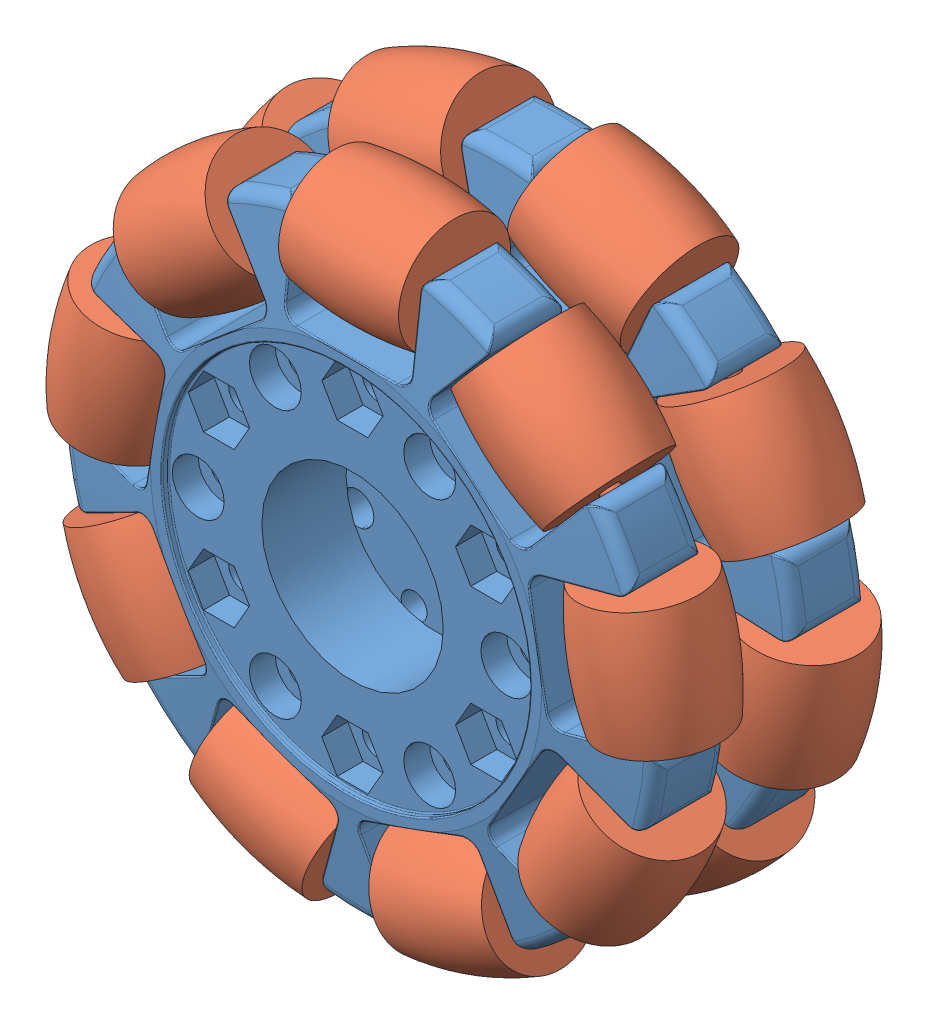
SolidWorks assembly omniwheel_complete, configuration Default. Lengths in mm.
Overall size (125.71 125.69 40.4).
21 component instances, 3 part files, 11 mates.
Components (placement in the parent):
- omniwheel_1-1: omniwheel_1 [Default] at origin size (91.98 92.06 15.75)
- omniwheel_1-3: omniwheel_1 [Default] at (0 0 -36.4) x (-0.5 -0.866025 0) z (0 0 -1) size (91.98 92.06 15.75)
- subwheel-1: subwheel [Default] at (0 -1 -7.5) size (24.1 19 19)
- subwheel-2: subwheel [Default] at (-0.6428 -0.766 -7.5) x (0.766044 -0.642788 0) z (0 0 1) size (24.1 19 19)
- subwheel-3: subwheel [Default] at (-0.9848 -0.1736 -7.5) x (0.173648 -0.984808 0) z (0 0 1) size (24.1 19 19)
- subwheel-4: subwheel [Default] at (-0.866 0.5 -7.5) x (-0.5 -0.866025 0) z (0 0 1) size (24.1 19 19)
- subwheel-5: subwheel [Default] at (-0.342 0.9397 -7.5) x (-0.939693 -0.34202 0) z (0 0 1) size (24.1 19 19)
- subwheel-6: subwheel [Default] at (0.342 0.9397 -7.5) x (-0.939693 0.34202 0) z (0 0 1) size (24.1 19 19)
- subwheel-7: subwheel [Default] at (0.866 0.5 -7.5) x (-0.5 0.866025 0) z (0 0 1) size (24.1 19 19)
- subwheel-8: subwheel [Default] at (0.9848 -0.1736 -7.5) x (0.173648 0.984808 0) z (0 0 1) size (24.1 19 19)
- subwheel-9: subwheel [Default] at (0.6428 -0.766 -7.5) x (0.766044 0.642788 0) z (0 0 1) size (24.1 19 19)
- subwheel-10: subwheel [Default] at (-80.7542 -14.2392 -28.9) x (0.173648 -0.984808 0) z (0 0 1) size (24.1 19 19)
- subwheel-11: subwheel [Default] at (-52.7086 -62.8156 -28.9) x (0.766044 -0.642788 0) z (0 0 1) size (24.1 19 19)
- subwheel-12: subwheel [Default] at (0 -82 -28.9) size (24.1 19 19)
- subwheel-13: subwheel [Default] at (52.7086 -62.8156 -28.9) x (0.766044 0.642788 0) z (0 0 1) size (24.1 19 19)
- subwheel-14: subwheel [Default] at (80.7542 -14.2392 -28.9) x (0.173648 0.984808 0) z (0 0 1) size (24.1 19 19)
- subwheel-15: subwheel [Default] at (71.0141 41 -28.9) x (-0.5 0.866025 0) z (0 0 1) size (24.1 19 19)
- subwheel-16: subwheel [Default] at (28.0457 77.0548 -28.9) x (-0.939693 0.34202 0) z (0 0 1) size (24.1 19 19)
- subwheel-17: subwheel [Default] at (-28.0457 77.0548 -28.9) x (-0.939693 -0.34202 0) z (0 0 1) size (24.1 19 19)
- subwheel-18: subwheel [Default] at (-71.0141 41 -28.9) x (-0.5 -0.866025 0) z (0 0 1) size (24.1 19 19)
- montageschijf-1: montageschijf [buitenschijf] at (0 0 -35.4) x (-0.5 -0.866025 0) z (0 0 -1) (suppressed, hidden)
Mates (geometry in assembly coordinates):
- Distance2: distance = 36.4 mm anti-aligned: plane of omniwheel_1-1 through (0 -5.8824 0) normal (0 0 1); plane of omniwheel_1-3 through (5.0943 -2.9412 -36.4) normal (0 0 -1)
- Concentric1: concentric anti-aligned: cylinder of omniwheel_1-1 through (0 0 -7.5) axis (0 0 1) radius 14; cylinder of omniwheel_1-3 through (0 0 -28.9) axis (0 0 -1) radius 14
- Angle1: planar angle = 1.047198 rad aligned: line of omniwheel_1-1 through (32 0 14) axis (0 0 1); line of omniwheel_1-3 through (-12.1244 7 -36.4) axis (-0.866025 0.5 0)
- Concentric8: concentric aligned: cylinder of omniwheel_1-1 through (9.75 40.5 -7.5) axis (-1 0 0) radius 1.5; cylinder of subwheel-1 through (-9.25 40.5 -7.5) axis (-1 0 0) radius 1.4
- Distance4: distance = 0.5 mm anti-aligned: plane of subwheel-1 through (9.25 49.1541 -7.5) normal (1 0 0); plane of omniwheel_1-1 through (9.75 -5.8824 -7.5) normal (-1 0 0)
- Concentric9: concentric anti-aligned: cylinder of omniwheel_1-3 through (-41.5778 2.5691 -28.9) axis (0.173648 -0.984808 0) radius 1.5; cylinder of subwheel-10 through (-41.491 2.0767 -28.9) axis (-0.173648 0.984808 0) radius 1.4
- Distance5: distance = 0.5 mm anti-aligned: plane of subwheel-10 through (-29.7558 -14.6394 -28.9) normal (0.173648 -0.984808 0); plane of omniwheel_1-3 through (7.4861 -8.5804 -28.9) normal (-0.173648 0.984808 0)
- InPlace2: in place: plane of ? through (5.0943 -2.9412 -22.4) normal (0 0 1); plane of ? through (0 0 -22.4) normal (0 0 1); moOrthogonalPlaneRef_w of ? through (5.0943 -2.9412 -22.4) normal (0 0 1); unknown of ?; plane of ? through (5.0943 -2.9412 -22.4) normal (0 0 1); unknown of ?; plane of omniwheel_1-3 through (5.0943 -2.9412 -35.4) normal (0 0 -1); unknown of montageschijf-1
- Coincident6: coincident aligned: plane of omniwheel_1-3; plane of montageschijf-1
- Coincident7: coincident aligned: moOrthogonalPlaneRef_w of omniwheel_1-3; plane of montageschijf-1 through (0 0 -35.4) normal (-0.866025 0.5 0)
- Coincident8: coincident anti-aligned: moOrthogonalPlaneRef_w of omniwheel_1-3; plane of montageschijf-1 through (0 0 -35.4) normal (-0.5 -0.866025 0)
